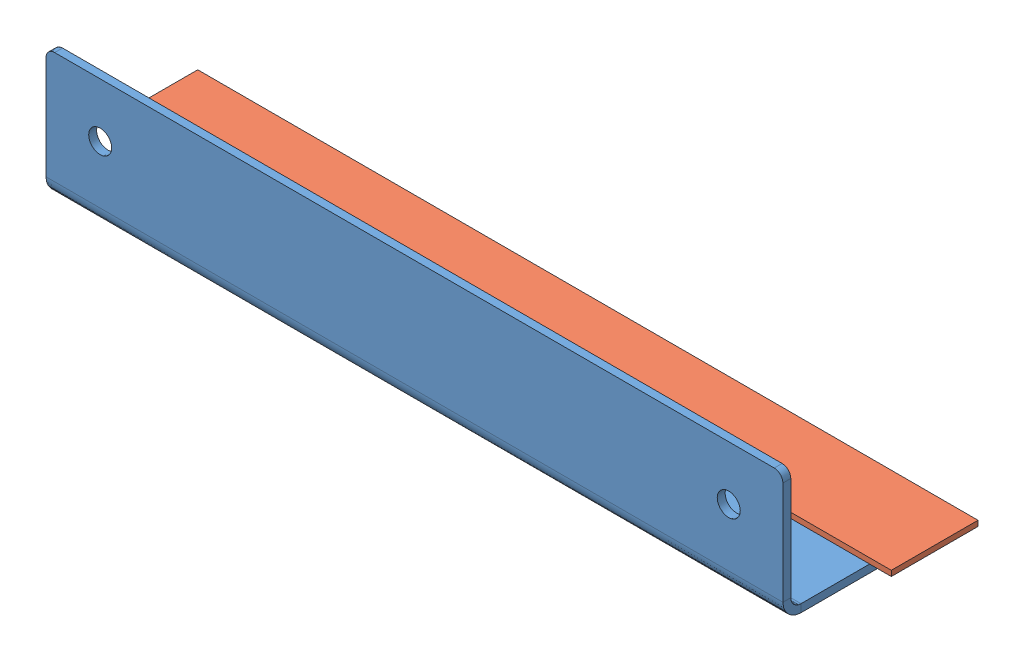
SolidWorks assembly GE-22337, configuration Default. Lengths in mm.
Overall size (228.6 38.1 50.8).
2 component instances, 2 part files, 6 mates.
Components (placement in the parent):
- GE-22325-1: GE-22325 [Default] at (-107.95 0 -2.3048) x (0 0 -1) z (1 0 0) size (50.8 38.1 215.9)
- Hook_1_9-1: Hook_1_9 [Default] at (-114.3 2.3048 -25.4) size (228.6 1.59 25.4)
Mates (geometry in assembly coordinates):
- Coincident3: coincident anti-aligned: plane of GE-22325-1 through (-107.95 2.3048 -2.3048) normal (0 1 0); plane of Hook_1_9-1 through (-114.3 2.3048 -25.4) normal (0 -1 0)
- Coincident4: coincident aligned: plane of GE-22325-1 through (107.95 0 -50.8) normal (0 0 -1); plane of Hook_1_9-1 through (-114.3 3.8923 -50.8) normal (0 0 -1)
- Width1: width aligned: plane of Hook_1_9-1 through (-114.3 3.8923 -25.4) normal (-1 0 0); plane of Hook_1_9-1 through (114.3 3.8923 -25.4) normal (1 0 0); plane of GE-22325-1 through (-107.95 0 -50.8) normal (-1 0 0); plane of GE-22325-1 through (107.95 0 -2.3048) normal (1 0 0)
- Coincident5: coincident aligned: plane of GE-22325-1 through (-107.95 0 0) normal (0 0 1)
- Coincident6: coincident anti-aligned: plane of GE-22325-1 through (-107.95 0 -2.3048) normal (0 -1 0)
- Symmetric1: symmetric aligned: plane of GE-22325-1 through (107.95 0 0) normal (1 0 0); plane of GE-22325-1 through (-107.95 0 0) normal (-1 0 0)
